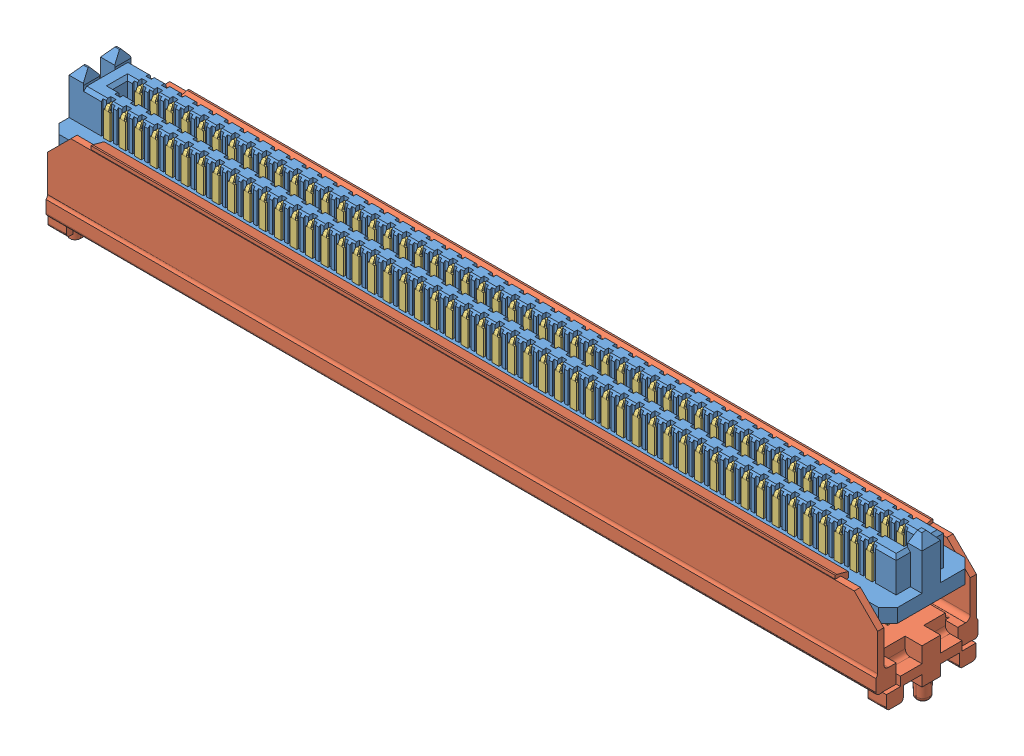
SolidWorks assembly SEAM_50_07_0_L_04_2_A_K_TR, configuration Default. Lengths in mm.
Overall size (68.48 11.86 8.33).
5 component instances, 5 part files, 0 mates.
Components (placement in the parent):
- _SEAM_50_07_0_L_04_1_A_K_TR_body_2-1: _SEAM_50_07_0_L_04_1_A_K_TR_body_2 [Default] at origin size (68.48 6.35 7.06)
- _SEAM_50_07_0_L_04_1_A_K_TR_spacer_4-1: _SEAM_50_07_0_L_04_1_A_K_TR_spacer_4 [Default] at origin size (68.48 9.12 8.33)
- _SEAM_50_07_0_L_04_1_A_K_TR_conn_6-1: _SEAM_50_07_0_L_04_1_A_K_TR_conn_6 [Default] at origin size (67.97 9.28 6.55)
- _SEAM_K_Pad_04_8-1: _SEAM_K_Pad_04_8 [Default] at (0 2.6924 0) size (5.99 0.13 5.99) (hidden)
- _SEAM_Triangle_10-1: _SEAM_Triangle_10 [Default] at (32.2834 1.2954 -1.6764) x (-1 0 0) z (0 0 -1) size (1.02 1.27 0.13)
